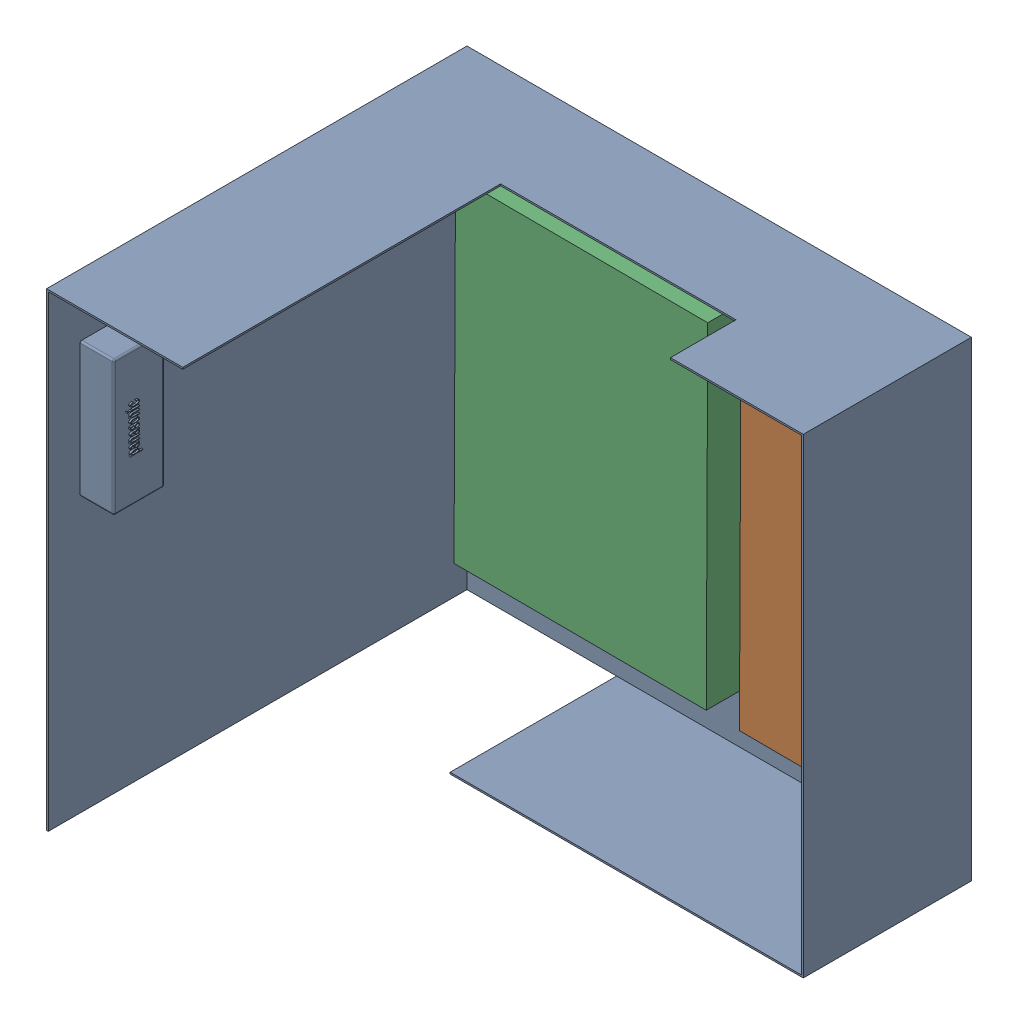
SolidWorks assembly 装配体1, configuration 默认. Lengths in mm.
Overall size (3000 2800 2500).
3 component instances, 3 part files, 3 mates.
Components (placement in the parent):
- room-1: room [默认] at (-12.7421 171.485 -1143.672) size (3000 2800 2500)
- small_bed-1: small_bed [默认] at (972.1422 364.0318 -633.672) x (0.99999 -0.004396 0) z (0 0 -1) size (700 2000 500)
- big_bed-1: big_bed [默认] at (-325.2947 375.2569 -633.672) x (0.99999 -0.004396 0) z (0 0 -1) size (1500 2000 500)
Mates (geometry in assembly coordinates):
- 重合1: coincident anti-aligned: plane of room-1 through (-12.7421 171.485 -1133.672) normal (0 0 1); plane of small_bed-1 through (972.1422 364.0318 -1133.672) normal (0 0 -1)
- 重合3: coincident anti-aligned: plane of room-1 through (-12.7421 171.485 -1133.672) normal (0 0 1); plane of big_bed-1 through (-325.2947 375.2569 -1133.672) normal (0 0 -1)
- 平行3: parallel anti-aligned: plane of small_bed-1 through (626.5411 1365.5606 -833.672) normal (-0.99999 0.004396 0); plane of big_bed-1 through (429.0936 1371.9506 -833.672) normal (0.99999 -0.004396 0)
